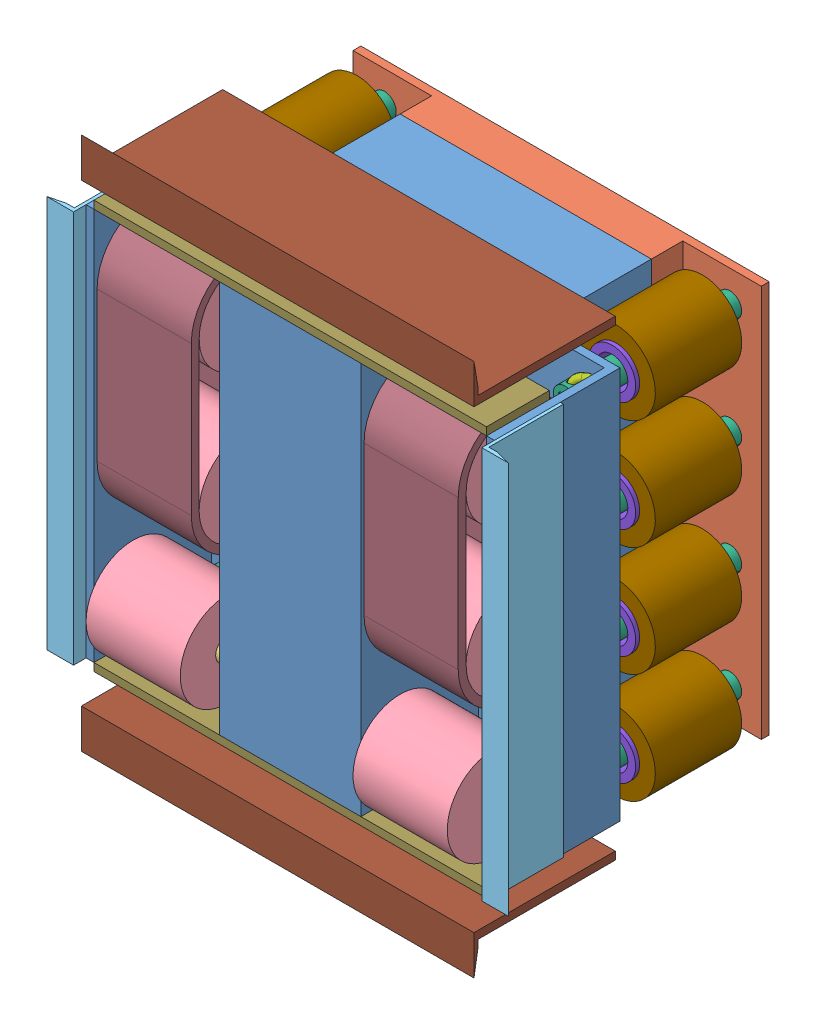
SolidWorks assembly Assemblage complet, configuration Défaut. Lengths in mm.
Overall size (309.58 340 213.27).
72 component instances, 15 part files, 71 mates.
Components (placement in the parent):
- chassis inferieur(essai finale)-1: chassis inferieur(essai finale) [Défaut] at (47.5942 -133.5608 312.5001) size (260 250 150)
- chassis superieur-1: chassis superieur [Défaut] at (82.5942 -133.5608 147.5001) size (260 250 25)
- axe roues-2: axe roues [Défaut] at (117.5942 -98.5608 302.5001) x (0 0 1) z (-1 0 0) size (15.31 15.16 240)
- roue-2: roue [Défaut] at (117.5942 -98.5608 302.5001) x (0 0.765826 -0.643048) z (-1 0 0) size (60 60 60)
- roue-3: roue [Défaut] at (-52.4058 -98.5608 302.5001) x (0 -0.992301 -0.123848) z (-1 0 0) size (60 60 60)
- axe roues-4: axe roues [Défaut] at (117.5942 81.4392 290.5001) x (0 0.996729 -0.080816) z (-1 0 0) size (15.31 15.16 240)
- roue-4: roue [Défaut] at (-52.4058 -13.5608 290.5001) x (0 0.718226 0.69581) z (-1 0 0) size (60 60 60)
- roue-5: roue [Défaut] at (-52.4058 81.4392 290.5001) x (0 -0.999207 0.039804) z (-1 0 0) size (60 60 60)
- roue-6: roue [Défaut] at (117.5942 81.4392 290.5001) x (0 -0.541474 -0.840717) z (-1 0 0) size (60 60 60)
- roue-7: roue [Défaut] at (117.5942 -13.5608 290.5001) x (0 0.020188 0.999796) z (-1 0 0) size (60 60 60)
- pare coté-1: pare coté [Défaut] at (132.5942 -133.5608 325.5001) x (0 -1 0) z (1 0 0) size (250 50 17)
- pare coté-2: pare coté [Défaut] at (-127.4058 116.4392 325.5001) x (0 1 0) z (-1 0 0) size (250 50 17)
- axe galet-5: axe galet [Défaut] at (112.5942 96.4392 132.5001) x (0.997414 0.07187 0) z (0 0 1) size (15 15 122)
- attache 1-1: attache 1 [Défaut] at (111.7852 106.9082 137.5001) x (0.07187 -0.997414 0) z (-0.523438 -0.037717 0.851228) size (25 12.5 5)
- attache 1-2: attache 1 [Défaut] at (113.2944 85.9625 247.5001) x (-0.07187 0.997414 0) z (-0.523438 -0.037717 -0.851228) size (25 12.5 5)
- Assemblage(galet)-1: Assemblage(galet) [Défaut] at (102.0839 107.1662 102.5001) x (-0.858499 0.512816 0) z (0 0 1) size (70.7 70.7 60)
  - galet(inside)-1: galet(inside) [Défaut] at (-14.524 3.8193 60) size (30 30 60)
  - galet(outside)-1: galet(outside) [Défaut] at (-14.524 3.8193 62.5) x (0.717031 0.697042 0) z (0 0 1) size (50 50 55)
- attache 1-3: attache 1 [Défaut] at (113.2944 15.9625 247.5001) x (-0.07187 0.997414 0) z (-0.523438 -0.037717 -0.851228) size (25 12.5 5)
- attache 1-4: attache 1 [Défaut] at (113.2944 -54.0375 247.5001) x (-0.07187 0.997414 0) z (-0.523438 -0.037717 -0.851228) size (25 12.5 5)
- attache 1-5: attache 1 [Défaut] at (113.2944 -124.0375 247.5001) x (-0.07187 0.997414 0) z (-0.523438 -0.037717 -0.851228) size (25 12.5 5)
- attache 1-6: attache 1 [Défaut] at (111.7852 36.9082 137.5001) x (0.07187 -0.997414 0) z (-0.523438 -0.037717 0.851228) size (25 12.5 5)
- attache 1-7: attache 1 [Défaut] at (111.7852 -33.0918 137.5001) x (0.07187 -0.997414 0) z (-0.523438 -0.037717 0.851228) size (25 12.5 5)
- attache 1-8: attache 1 [Défaut] at (111.7852 -103.0918 137.5001) x (0.07187 -0.997414 0) z (-0.523438 -0.037717 0.851228) size (25 12.5 5)
- axe galet-6: axe galet [Défaut] at (112.5942 26.4392 132.5001) x (0.997414 0.07187 0) z (0 0 1) size (15 15 122)
- axe galet-7: axe galet [Défaut] at (112.5942 -43.5608 132.5001) x (0.997414 0.07187 0) z (0 0 1) size (15 15 122)
- axe galet-8: axe galet [Défaut] at (112.5942 -113.5608 132.5001) x (0.997414 0.07187 0) z (0 0 1) size (15 15 122)
- Assemblage(galet)-2: Assemblage(galet) [Défaut] at (102.0839 37.1662 102.5001) x (-0.858499 0.512816 0) z (0 0 1) size (70.7 70.7 60)
  - galet(inside)-1: galet(inside) [Défaut] at (-14.524 3.8193 60) size (30 30 60)
  - galet(outside)-1: galet(outside) [Défaut] at (-14.524 3.8193 62.5) x (0.717031 0.697042 0) z (0 0 1) size (50 50 55)
- Assemblage(galet)-3: Assemblage(galet) [Défaut] at (102.0839 -32.8338 102.5001) x (-0.858499 0.512816 0) z (0 0 1) size (70.7 70.7 60)
  - galet(inside)-1: galet(inside) [Défaut] at (-14.524 3.8193 60) size (30 30 60)
  - galet(outside)-1: galet(outside) [Défaut] at (-14.524 3.8193 62.5) x (0.717031 0.697042 0) z (0 0 1) size (50 50 55)
- Assemblage(galet)-4: Assemblage(galet) [Défaut] at (102.0839 -102.8338 102.5001) x (-0.858499 0.512816 0) z (0 0 1) size (70.7 70.7 60)
  - galet(inside)-1: galet(inside) [Défaut] at (-14.524 3.8193 60) size (30 30 60)
  - galet(outside)-1: galet(outside) [Défaut] at (-14.524 3.8193 62.5) x (0.717031 0.697042 0) z (0 0 1) size (50 50 55)
- attache 1-9: attache 1 [Défaut] at (-106.7056 85.9625 247.5001) x (-0.07187 0.997414 0) z (-0.523438 -0.037717 -0.851228) size (25 12.5 5)
- attache 1-10: attache 1 [Défaut] at (-108.2148 106.9082 137.5001) x (0.07187 -0.997414 0) z (-0.523438 -0.037717 0.851228) size (25 12.5 5)
- axe galet-9: axe galet [Défaut] at (-107.4058 96.4392 132.5001) x (0.997414 0.07187 0) z (0 0 1) size (15 15 122)
- Assemblage(galet)-5: Assemblage(galet) [Défaut] at (-117.9161 107.1662 102.5001) x (-0.858499 0.512816 0) z (0 0 1) size (70.7 70.7 60)
  - galet(inside)-1: galet(inside) [Défaut] at (-14.524 3.8193 60) size (30 30 60)
  - galet(outside)-1: galet(outside) [Défaut] at (-14.524 3.8193 62.5) x (0.717031 0.697042 0) z (0 0 1) size (50 50 55)
- attache 1-11: attache 1 [Défaut] at (-106.7056 15.9625 247.5001) x (-0.07187 0.997414 0) z (-0.523438 -0.037717 -0.851228) size (25 12.5 5)
- attache 1-12: attache 1 [Défaut] at (-106.7056 -54.0375 247.5001) x (-0.07187 0.997414 0) z (-0.523438 -0.037717 -0.851228) size (25 12.5 5)
- attache 1-13: attache 1 [Défaut] at (-106.7056 -124.0375 247.5001) x (-0.07187 0.997414 0) z (-0.523438 -0.037717 -0.851228) size (25 12.5 5)
- attache 1-14: attache 1 [Défaut] at (-108.2148 36.9082 137.5001) x (0.07187 -0.997414 0) z (-0.523438 -0.037717 0.851228) size (25 12.5 5)
- attache 1-15: attache 1 [Défaut] at (-108.2148 -33.0918 137.5001) x (0.07187 -0.997414 0) z (-0.523438 -0.037717 0.851228) size (25 12.5 5)
- attache 1-16: attache 1 [Défaut] at (-108.2148 -103.0918 137.5001) x (0.07187 -0.997414 0) z (-0.523438 -0.037717 0.851228) size (25 12.5 5)
- axe galet-10: axe galet [Défaut] at (-107.4058 26.4392 132.5001) x (0.997414 0.07187 0) z (0 0 1) size (15 15 122)
- axe galet-11: axe galet [Défaut] at (-107.4058 -43.5608 132.5001) x (0.997414 0.07187 0) z (0 0 1) size (15 15 122)
- axe galet-12: axe galet [Défaut] at (-107.4058 -113.5608 132.5001) x (0.997414 0.07187 0) z (0 0 1) size (15 15 122)
- Assemblage(galet)-6: Assemblage(galet) [Défaut] at (-117.9161 37.1662 102.5001) x (-0.858499 0.512816 0) z (0 0 1) size (70.7 70.7 60)
  - galet(inside)-1: galet(inside) [Défaut] at (-14.524 3.8193 60) size (30 30 60)
  - galet(outside)-1: galet(outside) [Défaut] at (-14.524 3.8193 62.5) x (0.717031 0.697042 0) z (0 0 1) size (50 50 55)
- Assemblage(galet)-7: Assemblage(galet) [Défaut] at (-117.9161 -32.8338 102.5001) x (-0.858499 0.512816 0) z (0 0 1) size (70.7 70.7 60)
  - galet(inside)-1: galet(inside) [Défaut] at (-14.524 3.8193 60) size (30 30 60)
  - galet(outside)-1: galet(outside) [Défaut] at (-14.524 3.8193 62.5) x (0.717031 0.697042 0) z (0 0 1) size (50 50 55)
- Assemblage(galet)-8: Assemblage(galet) [Défaut] at (-117.9161 -102.8338 102.5001) x (-0.858499 0.512816 0) z (0 0 1) size (70.7 70.7 60)
  - galet(inside)-1: galet(inside) [Défaut] at (-14.524 3.8193 60) size (30 30 60)
  - galet(outside)-1: galet(outside) [Défaut] at (-14.524 3.8193 62.5) x (0.717031 0.697042 0) z (0 0 1) size (50 50 55)
- appuie pare-1: appuie pare [Défaut] at (47.5942 116.4392 277.5001) x (1 0 0) z (0 1 0) size (90 35 20)
- appuie pare-2: appuie pare [Défaut] at (47.5942 -133.5608 242.5001) x (1 0 0) z (0 -1 0) size (90 35 20)
- pare avant-1: pare avant [Défaut] at (127.5942 136.4392 325.5001) x (1 0 0) z (0 1 0) size (250 90 25)
- pare avant-2: pare avant [Défaut] at (-122.4058 -153.5608 325.5001) x (-1 0 0) z (0 -1 0) size (250 90 25)
- suport capteurs-1: suport capteurs [Défaut] at (127.5942 116.4392 317.5001) x (1 0 0) z (0 1 0) size (250 40 5)
- suport capteurs-2: suport capteurs [Défaut] at (127.5942 -138.5608 317.5001) x (1 0 0) z (0 1 0) size (250 40 5)
- courroie-1: courroie [Défaut] at (57.5942 81.4392 290.5001) x (0 -1 0) z (1 0 0) size (165 70 60)
- courroie-2: courroie [Défaut] at (-112.4058 -13.5608 290.5001) x (0 1 0) z (1 0 0) size (165 70 60)
- moteur dc-1: moteur dc [Défaut] at (22.0942 88.4392 265.5001) x (1 0 0) z (0 -1 0) size (44 72 145.16)
- axe moteur-1: axe moteur [Défaut] at (29.5942 -13.5608 290.5001) x (0 -0.661741 -0.749732) z (1 0 0) size (15 15 95)
- moteur dc-2: moteur dc [Défaut] at (-16.9058 -115.5608 265.5001) x (-1 0 0) z (0 1 0) size (44 72 145.16)
- axe moteur-2: axe moteur [Défaut] at (-24.4058 -13.5608 290.5001) x (0 0.393114 -0.91949) z (-1 0 0) size (15 15 95)
Mates (geometry in assembly coordinates):
- Parallèle1: parallel anti-aligned: plane of chassis inferieur(essai finale)-1 through (47.5942 -133.5608 237.5001) normal (0 0 -1); plane of chassis superieur-1 through (82.5942 -133.5608 147.5001) normal (0 0 1)
- Coïncidente4: coincident aligned: plane of chassis inferieur(essai finale)-1 through (47.5942 116.4392 317.5001) normal (0 1 0); plane of chassis superieur-1 through (82.5942 116.4392 167.5001) normal (0 1 0)
- Coaxiale3: concentric anti-aligned: cylinder of chassis inferieur(essai finale)-1 through (127.5942 -98.5608 302.5001) axis (-1 0 0) radius 10; cylinder of axe roues-2 through (-112.4058 -98.5608 302.5001) axis (1 0 0) radius 5
- Distance2: distance = 5 mm anti-aligned: plane of axe roues-2 through (-47.4058 -98.5608 302.5001) normal (1 0 0); plane of chassis inferieur(essai finale)-1 through (-42.4058 -133.5608 317.5001) normal (-1 0 0)
- Coaxiale4: concentric anti-aligned: cylinder of axe roues-2 through (-112.4058 -98.5608 302.5001) axis (1 0 0) radius 5; cylinder of roue-2 through (117.5942 -98.5608 302.5001) axis (-1 0 0) radius 5
- Coïncidente11: coincident anti-aligned: plane of axe roues-2 through (57.5942 -98.5608 302.5001) normal (1 0 0); plane of roue-2 through (57.5942 -98.5608 302.5001) normal (-1 0 0)
- Coaxiale5: concentric anti-aligned: cylinder of axe roues-2 through (-112.4058 -98.5608 302.5001) axis (1 0 0) radius 5; cylinder of roue-3 through (-52.4058 -98.5608 302.5001) axis (-1 0 0) radius 5
- Coïncidente12: coincident anti-aligned: plane of axe roues-2 through (-112.4058 -98.5608 302.5001) normal (1 0 0); plane of roue-3 through (-112.4058 -98.5608 302.5001) normal (-1 0 0)
- Coaxiale7: concentric anti-aligned: cylinder of chassis inferieur(essai finale)-1 through (127.5942 81.4392 290.5001) axis (-1 0 0) radius 10; cylinder of axe roues-4 through (-112.4058 81.4392 290.5001) axis (1 0 0) radius 5
- Distance4: distance = 5 mm anti-aligned: plane of axe roues-4 through (-47.4058 81.4392 290.5001) normal (1 0 0); plane of chassis inferieur(essai finale)-1 through (-42.4058 -133.5608 317.5001) normal (-1 0 0)
- Coaxiale8: concentric anti-aligned: cylinder of axe roues-4 through (-112.4058 81.4392 290.5001) axis (1 0 0) radius 5; cylinder of roue-6 through (117.5942 81.4392 290.5001) axis (-1 0 0) radius 5
- Coïncidente15: coincident anti-aligned: plane of axe roues-4 through (57.5942 81.4392 290.5001) normal (1 0 0); plane of roue-6 through (57.5942 81.4392 290.5001) normal (-1 0 0)
- Coaxiale10: concentric anti-aligned: cylinder of axe roues-4 through (-112.4058 81.4392 290.5001) axis (1 0 0) radius 5; cylinder of roue-5 through (-52.4058 81.4392 290.5001) axis (-1 0 0) radius 5
- Coïncidente17: coincident anti-aligned: plane of axe roues-4 through (-52.4058 81.4392 290.5001) normal (-1 0 0); plane of roue-5 through (-52.4058 81.4392 290.5001) normal (1 0 0)
- Coïncidente41: coincident aligned: plane of chassis inferieur(essai finale)-1 through (47.5942 116.4392 317.5001) normal (0 1 0); plane of chassis superieur-1 through (82.5942 116.4392 167.5001) normal (0 1 0)
- Coïncidente42: coincident aligned: plane of chassis inferieur(essai finale)-1 through (82.5942 116.4392 167.5001) normal (1 0 0); plane of chassis superieur-1 through (82.5942 -133.5608 167.5001) normal (1 0 0)
- Coïncidente43: coincident anti-aligned: plane of chassis inferieur(essai finale)-1 through (47.5942 -133.5608 167.5001) normal (0 0 -1); plane of chassis superieur-1 through (82.5942 -133.5608 167.5001) normal (0 0 1)
- Coïncidente50: coincident anti-aligned: plane of chassis inferieur(essai finale)-1 through (132.5942 -133.5608 312.5001) normal (1 0 0); plane of pare coté-1 through (132.5942 -133.5608 325.5001) normal (-1 0 0)
- Coïncidente52: coincident aligned: plane of chassis inferieur(essai finale)-1 through (47.5942 -133.5608 317.5001) normal (0 -1 0); plane of pare coté-1 through (134.5942 -133.5608 325.5001) normal (0 -1 0)
- Coïncidente53: coincident anti-aligned: plane of chassis inferieur(essai finale)-1 through (-127.4058 -133.5608 312.5001) normal (-1 0 0); plane of pare coté-2 through (-127.4058 116.4392 325.5001) normal (1 0 0)
- Coïncidente55: coincident aligned: plane of chassis inferieur(essai finale)-1 through (47.5942 116.4392 317.5001) normal (0 1 0); plane of pare coté-2 through (-129.4058 116.4392 325.5001) normal (0 1 0)
- Coaxiale14: concentric anti-aligned: cylinder of chassis superieur-1 through (112.5942 96.4392 137.5001) axis (0 0 1) radius 7.5; cylinder of axe galet-5 through (112.5942 96.4392 192.5001) axis (0 0 -1) radius 7.5
- Distance6: distance = 10 mm aligned: plane of axe galet-5 through (112.5942 96.4392 132.5001) normal (0 0 -1); plane of chassis superieur-1 through (82.5942 -133.5608 142.5001) normal (0 0 -1)
- Coaxiale15: concentric anti-aligned: cylinder of axe galet-5 through (108.7307 149.2983 137.5001) axis (0.07187 -0.997414 0) radius 2.5; cylinder of attache 1-1 through (112.8632 91.947 137.5001) axis (-0.07187 0.997414 0) radius 2.5
- Coaxiale19: concentric anti-aligned: cylinder of axe galet-5 through (108.7307 149.2983 137.5001) axis (0.07187 -0.997414 0) radius 2.5; cylinder of attache 1-1 through (112.8632 91.947 137.5001) axis (-0.07187 0.997414 0) radius 2.5
- Distance12: distance = 5 mm anti-aligned: plane of axe galet-5 through (115.3708 99.6471 131.5001) normal (-0.07187 0.997414 0); cylinder of attache 1-1 through (116.0303 107.2141 140.1241) axis (0.849027 0.061178 0.524795) radius 2.5
- Coaxiale21: concentric aligned: cylinder of axe galet-5 through (108.7307 149.2983 247.5001) axis (0.07187 -0.997414 0) radius 2.5; cylinder of attache 1-2 through (112.2164 100.9237 247.5001) axis (0.07187 -0.997414 0) radius 2.5
- Distance14: distance = 5 mm anti-aligned: cylinder of attache 1-2 through (117.5396 86.2684 244.8761) axis (0.849027 0.061178 -0.524795) radius 2.5; plane of axe galet-5 through (115.802 93.6626 253.5001) normal (0.07187 -0.997414 0)
- Coaxiale22: concentric aligned: cylinder of axe galet-5 through (112.5942 96.4392 192.5001) axis (0 0 -1) radius 7.5; cylinder of Assemblage(galet)-1/galet(inside)-1 through (112.5942 96.4392 222.5001) axis (0 0 -1) radius 10
- Distance15: distance = 15 mm anti-aligned: plane of Assemblage(galet)-1/galet(inside)-1 through (112.5942 96.4392 162.5001) normal (0 0 -1); plane of chassis superieur-1 through (82.5942 -133.5608 147.5001) normal (0 0 1)
- Tangent23: tangent: plane of chassis inferieur(essai finale)-1 through (47.5942 -133.5608 242.5001) normal (0 0 1); torus of attache 1-2
- Tangent24: tangent: plane of chassis superieur-1 through (82.5942 -133.5608 142.5001) normal (0 0 -1); torus of attache 1-1
- Coïncidente56: coincident anti-aligned: plane of chassis inferieur(essai finale)-1 through (47.5942 -133.5608 317.5001) normal (0 -1 0); plane of appuie pare-2 through (47.5942 -133.5608 242.5001) normal (0 1 0)
- Coïncidente57: coincident anti-aligned: plane of chassis inferieur(essai finale)-1 through (47.5942 -133.5608 242.5001) normal (0 0 1); plane of appuie pare-2 through (47.5942 -153.5608 242.5001) normal (0 0 -1)
- Coïncidente58: coincident anti-aligned: plane of chassis inferieur(essai finale)-1 through (47.5942 116.4392 317.5001) normal (0 1 0); plane of appuie pare-1 through (47.5942 116.4392 277.5001) normal (0 -1 0)
- Coïncidente59: coincident anti-aligned: plane of chassis inferieur(essai finale)-1 through (47.5942 -133.5608 242.5001) normal (0 0 1); plane of appuie pare-1 through (47.5942 136.4392 242.5001) normal (0 0 -1)
- Coïncidente60: coincident aligned: plane of chassis inferieur(essai finale)-1 through (47.5942 -133.5608 317.5001) normal (1 0 0); plane of appuie pare-1 through (47.5942 136.4392 277.5001) normal (1 0 0)
- Coïncidente61: coincident aligned: plane of chassis inferieur(essai finale)-1 through (47.5942 -133.5608 317.5001) normal (1 0 0); plane of appuie pare-2 through (47.5942 -153.5608 242.5001) normal (1 0 0)
- Coïncidente62: coincident anti-aligned: plane of appuie pare-1 through (47.5942 136.4392 277.5001) normal (0 1 0); plane of pare avant-1 through (127.5942 136.4392 325.5001) normal (0 -1 0)
- Coïncidente65: coincident anti-aligned: plane of chassis inferieur(essai finale)-1 through (127.5942 -133.5608 312.5001) normal (-1 0 0); plane of pare avant-1 through (127.5942 141.4392 325.5001) normal (1 0 0)
- Coïncidente66: coincident anti-aligned: plane of appuie pare-2 through (47.5942 -153.5608 242.5001) normal (0 -1 0); plane of pare avant-2 through (-122.4058 -153.5608 325.5001) normal (0 1 0)
- Coïncidente68: coincident anti-aligned: plane of chassis inferieur(essai finale)-1 through (127.5942 -133.5608 312.5001) normal (-1 0 0); plane of pare avant-2 through (127.5942 -158.5608 325.5001) normal (1 0 0)
- Coïncidente69: coincident anti-aligned: plane of chassis inferieur(essai finale)-1 through (47.5942 116.4392 317.5001) normal (0 1 0); plane of suport capteurs-1 through (127.5942 116.4392 317.5001) normal (0 -1 0)
- Coïncidente70: coincident aligned: plane of pare avant-1 through (127.5942 141.4392 325.5001) normal (1 0 0); plane of suport capteurs-1 through (127.5942 121.4392 317.5001) normal (1 0 0)
- Coïncidente71: coincident aligned: plane of chassis inferieur(essai finale)-1 through (47.5942 -133.5608 317.5001) normal (0 0 1); plane of suport capteurs-1 through (127.5942 121.4392 317.5001) normal (0 0 1)
- Coïncidente72: coincident anti-aligned: plane of chassis inferieur(essai finale)-1 through (47.5942 -133.5608 317.5001) normal (0 -1 0); plane of suport capteurs-2 through (127.5942 -133.5608 317.5001) normal (0 1 0)
- Coïncidente73: coincident aligned: plane of pare avant-2 through (127.5942 -158.5608 325.5001) normal (1 0 0); plane of suport capteurs-2 through (127.5942 -133.5608 317.5001) normal (1 0 0)
- Coaxiale25: concentric anti-aligned: cylinder of roue-6 through (57.5942 81.4392 290.5001) axis (1 0 0) radius 30; cylinder of courroie-1 through (117.5942 81.4392 290.5001) axis (-1 0 0) radius 30
- Coaxiale26: concentric anti-aligned: cylinder of roue-7 through (57.5942 -13.5608 290.5001) axis (1 0 0) radius 30; cylinder of courroie-1 through (117.5942 -13.5608 290.5001) axis (-1 0 0) radius 30
- Coïncidente75: coincident aligned: plane of roue-7 through (117.5942 -13.5608 290.5001) normal (1 0 0); plane of courroie-1 through (117.5942 81.4392 290.5001) normal (1 0 0)
- Coaxiale30: concentric anti-aligned: cylinder of roue-5 through (-112.4058 81.4392 290.5001) axis (1 0 0) radius 30; cylinder of courroie-2 through (-52.4058 81.4392 290.5001) axis (-1 0 0) radius 30
- Coaxiale31: concentric anti-aligned: cylinder of roue-4 through (-112.4058 -13.5608 290.5001) axis (1 0 0) radius 30; cylinder of courroie-2 through (-52.4058 -13.5608 290.5001) axis (-1 0 0) radius 30
- Coïncidente76: coincident aligned: plane of roue-5 through (-112.4058 81.4392 290.5001) normal (-1 0 0); plane of courroie-2 through (-112.4058 -13.5608 290.5001) normal (-1 0 0)
- Coïncidente77: coincident aligned: plane of pare coté-1 through (134.5942 -133.5608 325.5001) normal (0 0 1); plane of courroie-1 through (117.5942 81.4392 325.5001) normal (0 0 1)
- Coïncidente78: coincident aligned: plane of pare coté-2 through (-129.4058 116.4392 325.5001) normal (0 0 1); plane of courroie-2 through (-52.4058 -13.5608 325.5001) normal (0 0 1)
- Coïncidente79: coincident aligned: plane of chassis inferieur(essai finale)-1 through (47.5942 -133.5608 317.5001) normal (0 0 1); plane of suport capteurs-2 through (127.5942 -133.5608 317.5001) normal (0 0 1)
- Coïncidente80: coincident aligned: plane of pare avant-2 through (-122.4058 -158.5608 325.5001) normal (0 0 1); plane of courroie-2 through (-52.4058 -13.5608 325.5001) normal (0 0 1)
- Coïncidente81: coincident aligned: plane of pare avant-1 through (127.5942 141.4392 325.5001) normal (0 0 1); plane of courroie-2 through (-52.4058 -13.5608 325.5001) normal (0 0 1)
- Parallèle2: parallel aligned: plane of chassis inferieur(essai finale)-1 through (47.5942 -133.5608 312.5001) normal (0 0 -1); plane of moteur dc-1 through (44.049 -41.5608 245.0001) normal (0 0 -1)
- Coaxiale34: concentric aligned: cylinder of chassis inferieur(essai finale)-1 through (127.5942 -13.5608 290.5001) axis (-1 0 0) radius 10; cylinder of moteur dc-1 through (39.5942 -13.5608 290.5001) axis (-1 0 0) radius 5.5
- Coïncidente83: coincident anti-aligned: plane of chassis inferieur(essai finale)-1 through (42.5942 111.4392 242.5001) normal (-1 0 0); plane of moteur dc-1 through (42.5942 -24.5195 273.5099) normal (1 0 0)
- Coïncidente84: coincident anti-aligned: plane of moteur dc-1 through (29.5942 88.4392 265.5001) normal (1 0 0); plane of axe moteur-1 through (29.5942 -13.5608 290.5001) normal (-1 0 0)
- Coïncidente85: coincident anti-aligned: plane of moteur dc-1 through (29.5942 -16.5608 288.768) normal (0 0.5 0.866025); plane of axe moteur-1 through (44.5942 -16.5608 288.768) normal (0 -0.5 -0.866025)
- Coaxiale35: concentric aligned: cylinder of moteur dc-1 through (39.5942 -13.5608 290.5001) axis (-1 0 0) radius 5.5; cylinder of axe moteur-1 through (119.5942 -13.5608 290.5001) axis (-1 0 0) radius 5
- Coïncidente86: coincident aligned: plane of roue-2 through (117.5942 -98.5608 302.5001) normal (1 0 0); plane of roue-7 through (117.5942 -13.5608 290.5001) normal (1 0 0)
- Parallèle3: parallel aligned: plane of chassis inferieur(essai finale)-1 through (47.5942 -133.5608 312.5001) normal (0 0 -1); plane of moteur dc-2 through (-38.8607 14.4392 245.0001) normal (0 0 -1)
- Coaxiale36: concentric anti-aligned: cylinder of chassis inferieur(essai finale)-1 through (127.5942 -13.5608 290.5001) axis (-1 0 0) radius 10; cylinder of moteur dc-2 through (-34.4058 -13.5608 290.5001) axis (1 0 0) radius 5.5
- Coïncidente88: coincident anti-aligned: plane of chassis inferieur(essai finale)-1 through (-37.4058 111.4392 242.5001) normal (1 0 0); plane of moteur dc-2 through (-37.4058 -2.602 273.5099) normal (-1 0 0)
- Coaxiale40: concentric aligned: cylinder of moteur dc-2 through (-34.4058 -13.5608 290.5001) axis (1 0 0) radius 5.5; cylinder of axe moteur-2 through (-114.4058 -13.5608 290.5001) axis (1 0 0) radius 5
- Coïncidente91: coincident anti-aligned: plane of moteur dc-2 through (-24.4058 -115.5608 265.5001) normal (-1 0 0); plane of axe moteur-2 through (-24.4058 -13.5608 290.5001) normal (1 0 0)
- Coïncidente92: coincident aligned: plane of roue-3 through (-112.4058 -98.5608 302.5001) normal (-1 0 0); plane of roue-4 through (-112.4058 -13.5608 290.5001) normal (-1 0 0)
